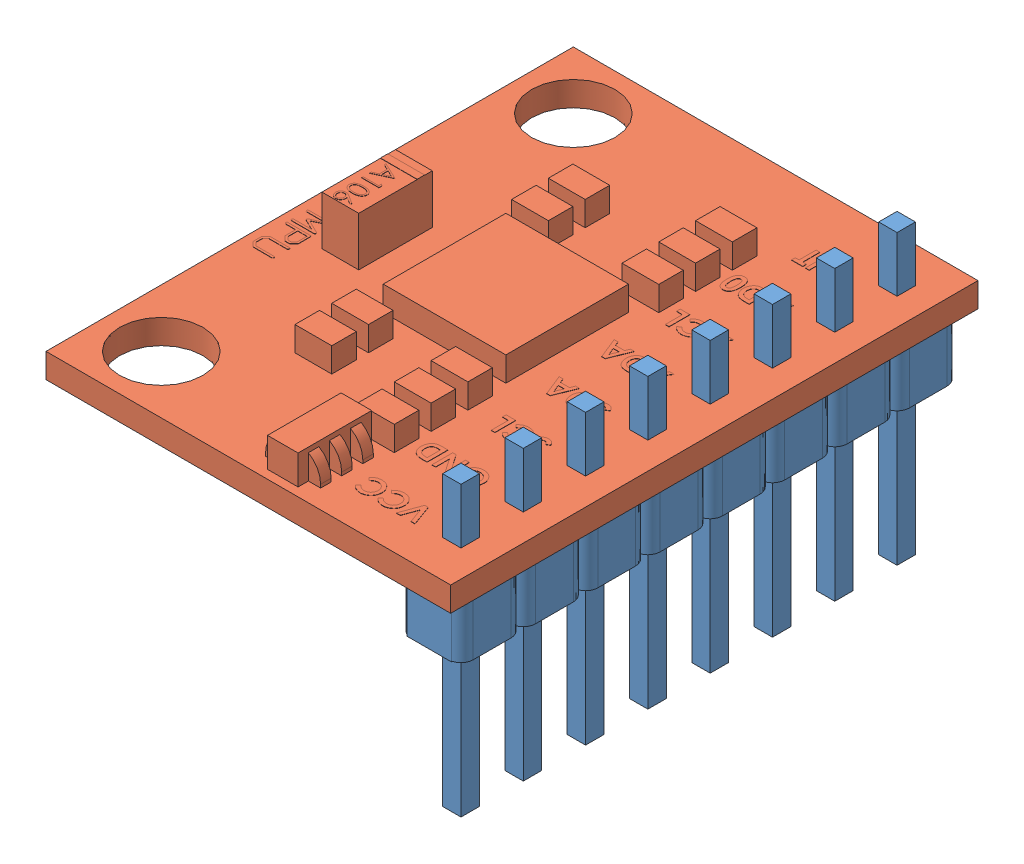
SolidWorks assembly ITG-MPU, configuration Predeterminado. Lengths in mm.
Overall size (16.5 11.75 21.5).
2 component instances, 2 part files, 3 mates.
Components (placement in the parent):
- 8 Header-Pin-1: 8 Header-Pin [Predeterminado] at (-3.9433 5.2392 11.5182) x (-1 0 0) z (0 0 1) size (2.54 11.75 20.34)
- Placa_Base-1: Placa_Base [Predeterminado] at (-10.7233 5.2392 20.4382) size (16.5 3.01 21.5)
Mates (geometry in assembly coordinates):
- Coincidente1: coincident: plane of assembly; plane of assembly; plane of 8 Header-Pin-1 through (-3.9433 5.2392 11.5182) normal (0 1 0); plane of Placa_Base-1 through (-10.7233 5.2392 20.4382) normal (0 -1 0)
- Distancia1: distance = 0.2 mm: line of assembly; line of assembly; line of 8 Header-Pin-1 through (-2.6733 5.2392 23.4482) axis (0 0 1); line of Placa_Base-1 through (-2.4733 5.2392 31.1882) axis (0 0 -1)
- Distancia2: distance = 0.6 mm: line of assembly; line of assembly; line of 8 Header-Pin-1 through (-3.0333 5.2392 30.5882) axis (-1 0 0); line of Placa_Base-1 through (-18.9733 5.2392 31.1882) axis (1 0 0)
